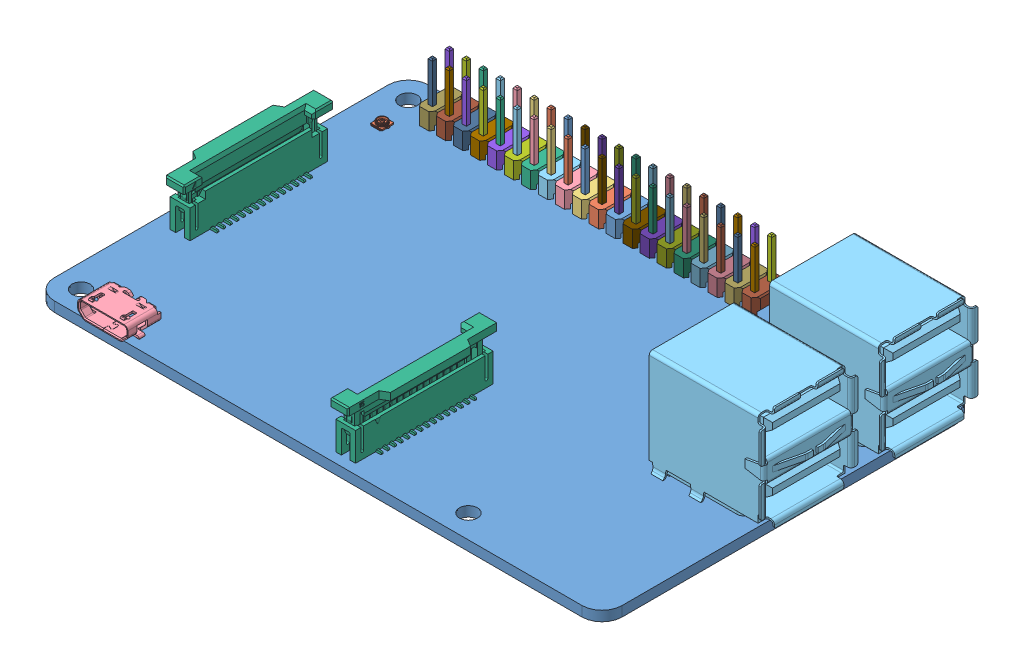
SolidWorks assembly tinker_pcb_assy_asm_0908_v2, configuration 預設. Lengths in mm.
Overall size (87.91 19.76 59.91).
72 component instances, 66 part files, 0 mates.
Components (placement in the parent):
- TINKER_MAIN_PCB-1: TINKER_MAIN_PCB [預設] at origin size (85 1.5 56)
- C_RF_CONN_20449-001E_IPEX_-1: C_RF_CONN_20449-001E_IPEX_ [預設] at (-37.77 1.55 -19.36) x (-1 0 0) z (0 1 0) size (2 2 0.6)
- C_MICROSD_SCHA4B0100_ALPS__-1: C_MICROSD_SCHA4B0100_ALPS__ [預設] at (-26.35 0 5.7625) x (0 -1 0) z (0 0 1) size (1.34 15.28 13.82)
- C_MICROUSB_MUC47_538235-1: C_MICROUSB_MUC47_538235 [預設] at (-31.9 2.77 23.35) size (7.5 3.46 5.2)
- C_LAN_JACK_UDE24_00019NN43_1_ASM-1: C_LAN_JACK_UDE24_00019NN43_1_ASM [預設] at (23.87 13.4713 69.2946) x (0 0 -1) z (1 0 0) (suppressed, hidden)
- C_AUDIO_JACK_TSH_5786R2_H3_105__ASM-1: C_AUDIO_JACK_TSH_5786R2_H3_105__ASM [預設] at (14.4 5.95 15.8985) x (0 0 -1) z (0 1 0) (suppressed, hidden)
- C_USB2_0_2X4P_UB11121_8SDH_4F-1: C_USB2_0_2X4P_UB11121_8SDH_4F [預設] at (27 9.84 -19.06) x (0 0 -1) z (0 -1 0) size (15.74 18.41 19.66)
- C_USB2_0_2X4P_UB11121_8SDH_4F-2: C_USB2_0_2X4P_UB11121_8SDH_4F [預設] at (27 9.84 -1.06) x (0 0 -1) z (0 -1 0) size (15.74 18.41 19.66)
- C_HDMI_CONN_QJ51191_LFS4_7F_ASM-1: C_HDMI_CONN_QJ51191_LFS4_7F_ASM [預設] at (-10.5 4.9 30.3) (suppressed, hidden)
- C_FPC_CONN_50611-01541_001_ACON-1: C_FPC_CONN_50611-01541_001_ACON [預設] at (4.35 1.73 16.45) x (0 0 -1) z (1 0 0) size (22.4 7.68 4.8)
- C_FPC_CONN_50611-01541_001_ACON-2: C_FPC_CONN_50611-01541_001_ACON [預設] at (-39.85 1.73 0) x (0 0 1) z (-1 0 0) size (22.4 7.68 4.8)
- C_HEADER_2X20P_PH40R53BANHA9_ASM-1: C_HEADER_2X20P_PH40R53BANHA9_ASM [預設] at (-35.4 1.55 -22) x (0 1 0) z (-1 0 0) size (11.1 5 50.8)
  - PRT0138-1: PRT0138 [預設] at origin size (11.1 0.64 0.64)
  - PRT0139-1: PRT0139 [預設] at origin size (11.1 0.64 0.64)
  - PRT0140-1: PRT0140 [預設] at origin size (11.1 0.64 0.64)
  - PRT0141-1: PRT0141 [預設] at origin size (11.1 0.64 0.64)
  - PRT0142-1: PRT0142 [預設] at origin size (11.1 0.64 0.64)
  - PRT0143-1: PRT0143 [預設] at origin size (11.1 0.64 0.64)
  - PRT0144-1: PRT0144 [預設] at origin size (11.1 0.64 0.64)
  - PRT0145-1: PRT0145 [預設] at origin size (11.1 0.64 0.64)
  - PRT0146-1: PRT0146 [預設] at origin size (11.1 0.64 0.64)
  - PRT0147-1: PRT0147 [預設] at origin size (11.1 0.64 0.64)
  - PRT0148-1: PRT0148 [預設] at origin size (11.1 0.64 0.64)
  - PRT0149-1: PRT0149 [預設] at origin size (11.1 0.64 0.64)
  - PRT0150-1: PRT0150 [預設] at origin size (11.1 0.64 0.64)
  - PRT0151-1: PRT0151 [預設] at origin size (11.1 0.64 0.64)
  - PRT0152-1: PRT0152 [預設] at origin size (11.1 0.64 0.64)
  - PRT0153-1: PRT0153 [預設] at origin size (11.1 0.64 0.64)
  - PRT0154-1: PRT0154 [預設] at origin size (11.1 0.64 0.64)
  - PRT0155-1: PRT0155 [預設] at origin size (11.1 0.64 0.64)
  - PRT0156-1: PRT0156 [預設] at origin size (11.1 0.64 0.64)
  - PRT0157-1: PRT0157 [預設] at origin size (11.1 0.64 0.64)
  - PRT0158-1: PRT0158 [預設] at origin size (11.1 0.64 0.64)
  - PRT0159-1: PRT0159 [預設] at origin size (11.1 0.64 0.64)
  - PRT0160-1: PRT0160 [預設] at origin size (11.1 0.64 0.64)
  - PRT0161-1: PRT0161 [預設] at origin size (11.1 0.64 0.64)
  - PRT0162-1: PRT0162 [預設] at origin size (11.1 0.64 0.64)
  - PRT0163-1: PRT0163 [預設] at origin size (11.1 0.64 0.64)
  - PRT0164-1: PRT0164 [預設] at origin size (11.1 0.64 0.64)
  - PRT0165-1: PRT0165 [預設] at origin size (11.1 0.64 0.64)
  - PRT0166-1: PRT0166 [預設] at origin size (11.1 0.64 0.64)
  - PRT0167-1: PRT0167 [預設] at origin size (11.1 0.64 0.64)
  - PRT0168-1: PRT0168 [預設] at origin size (11.1 0.64 0.64)
  - PRT0169-1: PRT0169 [預設] at origin size (11.1 0.64 0.64)
  - PRT0170-1: PRT0170 [預設] at origin size (11.1 0.64 0.64)
  - PRT0171-1: PRT0171 [預設] at origin size (11.1 0.64 0.64)
  - PRT0172-1: PRT0172 [預設] at origin size (11.1 0.64 0.64)
  - PRT0173-1: PRT0173 [預設] at origin size (11.1 0.64 0.64)
  - PRT0174-1: PRT0174 [預設] at origin size (11.1 0.64 0.64)
  - PRT0175-1: PRT0175 [預設] at origin size (11.1 0.64 0.64)
  - PRT0176-1: PRT0176 [預設] at origin size (11.1 0.64 0.64)
  - PRT0177-1: PRT0177 [預設] at origin size (11.1 0.64 0.64)
  - PRT0178-1: PRT0178 [預設] at origin size (2.5 5 2.54)
  - PRT0179-1: PRT0179 [預設] at origin size (2.5 5 2.54)
  - PRT0180-1: PRT0180 [預設] at origin size (2.5 5 2.54)
  - PRT0181-1: PRT0181 [預設] at origin size (2.5 5 2.54)
  - PRT0182-1: PRT0182 [預設] at origin size (2.5 5 2.54)
  - PRT0183-1: PRT0183 [預設] at origin size (2.5 5 2.54)
  - PRT0184-1: PRT0184 [預設] at origin size (2.5 5 2.54)
  - PRT0185-1: PRT0185 [預設] at origin size (2.5 5 2.54)
  - PRT0186-1: PRT0186 [預設] at origin size (2.5 5 2.54)
  - PRT0187-1: PRT0187 [預設] at origin size (2.5 5 2.54)
  - PRT0188-1: PRT0188 [預設] at origin size (2.5 5 2.54)
  - PRT0189-1: PRT0189 [預設] at origin size (2.5 5 2.54)
  - PRT0190-1: PRT0190 [預設] at origin size (2.5 5 2.54)
  - PRT0191-1: PRT0191 [預設] at origin size (2.5 5 2.54)
  - PRT0192-1: PRT0192 [預設] at origin size (2.5 5 2.54)
  - PRT0193-1: PRT0193 [預設] at origin size (2.5 5 2.54)
  - PRT0194-1: PRT0194 [預設] at origin size (2.5 5 2.54)
  - PRT0195-1: PRT0195 [預設] at origin size (2.5 5 2.54)
  - PRT0196-1: PRT0196 [預設] at origin size (2.5 5 2.54)
  - PRT0197-1: PRT0197 [預設] at origin size (2.5 5 2.54)
